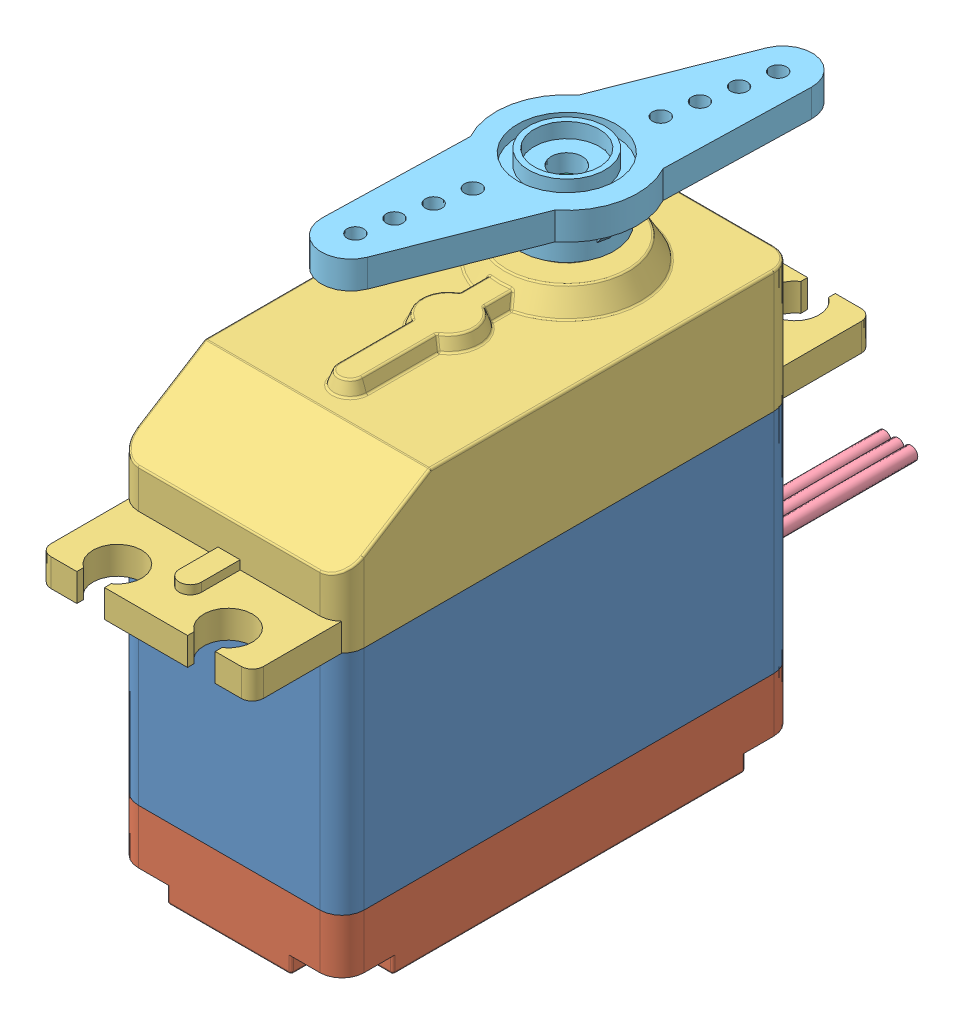
SolidWorks assembly SM-S4315R, CONTINUOUS ANALOG SERVO, configuration Default. Lengths in mm.
Overall size (20.4 46.65 67.9).
6 component instances, 6 part files, 14 mates.
Components (placement in the parent):
- SM-S4315R, CONTINUOUS ANALOG SERVO, BODY, MIDDLE-1: SM-S4315R, CONTINUOUS ANALOG SERVO, BODY, MIDDLE [Default] at origin size (20.4 20.5 41)
- SM-S4315R, CONTINUOUS ANALOG SERVO, BODY, BOTTOM-1: SM-S4315R, CONTINUOUS ANALOG SERVO, BODY, BOTTOM [Default] at (0 -16.65 0) size (20.4 6.4 41)
- SM-S4315R, CONTINUOUS ANALOG SERVO, BODY, TOP-1: SM-S4315R, CONTINUOUS ANALOG SERVO, BODY, TOP [Default] at (0 10.25 0) size (20.4 13 56)
- SM-S4315R, CONTINUOUS ANALOG SERVO, CONNECTOR-1: SM-S4315R, CONTINUOUS ANALOG SERVO, CONNECTOR [Default] at (0 -8.2 -20.5) size (6.8 4.1 19.4)
- SM-S4315R, CONTINUOUS ANALOG SERVO, HORN-1: SM-S4315R, CONTINUOUS ANALOG SERVO, HORN [Default] at (0 24.05 -10) x (-0.980077 0 -0.198618) z (0.198618 0 -0.980077) size (12.8 5.95 38.4)
- SM-S4315R, CONTINUOUS ANALOG SERVO, SHAFT-1: SM-S4315R, CONTINUOUS ANALOG SERVO, SHAFT [Default] at (0 9.55 -10) x (-0.980077 0 -0.198618) z (0.198618 0 -0.980077) size (5.76 17.5 5.8)
Mates (geometry in assembly coordinates):
- Coincident1: coordinate: point of assembly; point of SM-S4315R, CONTINUOUS ANALOG SERVO, BODY, MIDDLE-1; point of assembly
- Coincident3: coincident: plane of assembly through (0 0 0) normal (0 0 1); plane of SM-S4315R, CONTINUOUS ANALOG SERVO, BODY, BOTTOM-1 through (0 -16.65 0) normal (0 0 1); plane of assembly
- Coincident4: coincident: plane of assembly through (0 0 0) normal (1 0 0); plane of SM-S4315R, CONTINUOUS ANALOG SERVO, BODY, BOTTOM-1 through (0 -16.65 0) normal (1 0 0); plane of assembly
- Coincident5: coincident: plane of assembly through (0 0 0) normal (1 0 0); plane of SM-S4315R, CONTINUOUS ANALOG SERVO, BODY, TOP-1 through (0 10.25 0) normal (1 0 0); plane of assembly
- Coincident6: coincident: plane of assembly through (0 0 0) normal (0 0 1); plane of SM-S4315R, CONTINUOUS ANALOG SERVO, BODY, TOP-1 through (0 10.25 0) normal (0 0 1); plane of assembly
- Coincident10: coincident: plane of assembly through (0 0 0) normal (1 0 0); plane of SM-S4315R, CONTINUOUS ANALOG SERVO, CONNECTOR-1 through (0 -8.2 -20.5) normal (1 0 0); plane of assembly
- Coincident13: coincident: plane of assembly; plane of assembly; plane of SM-S4315R, CONTINUOUS ANALOG SERVO, HORN-1 through (0 24.05 -10) normal (-0.980077 0 -0.198618); plane of SM-S4315R, CONTINUOUS ANALOG SERVO, SHAFT-1 through (0 9.55 -10) normal (-0.980077 0 -0.198618)
- Coincident14: coordinate: point of assembly; point of SM-S4315R, CONTINUOUS ANALOG SERVO, BODY, MIDDLE-1; point of assembly
- Coincident15: coincident: plane of assembly; plane of assembly; plane of SM-S4315R, CONTINUOUS ANALOG SERVO, BODY, MIDDLE-1 through (0 -10.25 0) normal (0 -1 0); plane of SM-S4315R, CONTINUOUS ANALOG SERVO, BODY, BOTTOM-1 through (0 -10.25 0) normal (0 1 0)
- Coincident16: coincident: plane of assembly; plane of assembly; plane of SM-S4315R, CONTINUOUS ANALOG SERVO, BODY, MIDDLE-1 through (0 10.25 0) normal (0 1 0); plane of SM-S4315R, CONTINUOUS ANALOG SERVO, BODY, TOP-1 through (0 10.25 0) normal (0 -1 0)
- Concentric1: concentric: cylinder of assembly; cylinder of assembly; cylinder of SM-S4315R, CONTINUOUS ANALOG SERVO, BODY, TOP-1 through (0 10.25 -10) axis (0 1 0) radius 3; cylinder of SM-S4315R, CONTINUOUS ANALOG SERVO, SHAFT-1 through (0 23.05 -10) axis (0 1 0) radius 2.65
- Concentric2: concentric: cylinder of assembly; cylinder of assembly; cylinder of SM-S4315R, CONTINUOUS ANALOG SERVO, HORN-1 through (0 45.2519 -10) axis (0 -1 0) radius 4.25; cylinder of SM-S4315R, CONTINUOUS ANALOG SERVO, SHAFT-1 through (0 23.05 -10) axis (0 1 0) radius 2.65
- Coincident17: coincident: plane of assembly; plane of assembly; plane of SM-S4315R, CONTINUOUS ANALOG SERVO, HORN-1 through (0 27.05 -10) normal (0 -1 0); plane of SM-S4315R, CONTINUOUS ANALOG SERVO, SHAFT-1 through (0 27.05 -10) normal (0 1 0)
- Distance2: distance = 0.8 mm: plane of assembly; plane of assembly; plane of SM-S4315R, CONTINUOUS ANALOG SERVO, BODY, TOP-1 through (0 23.25 -10) normal (0 1 0); plane of SM-S4315R, CONTINUOUS ANALOG SERVO, HORN-1 through (0 24.05 -10) normal (0 -1 0)
